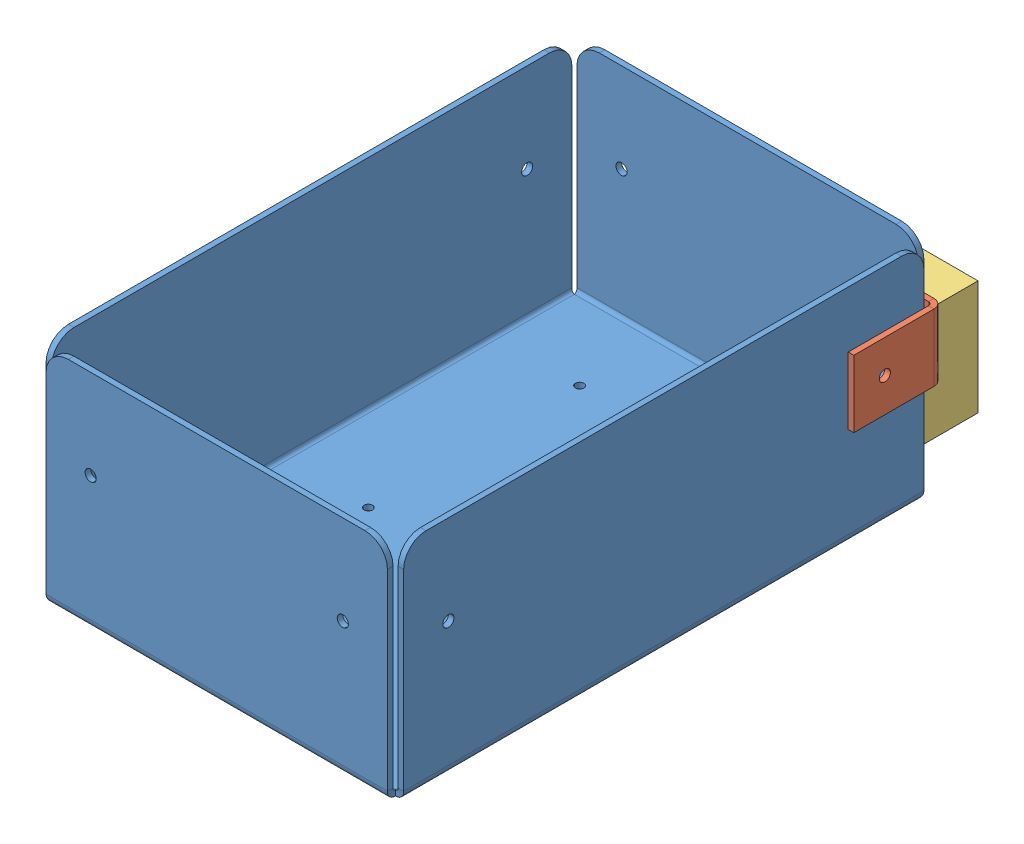
SolidWorks assembly Angle Placeholder, configuration Default. Lengths in mm.
Overall size (103.19 63.5 177.4).
3 component instances, 3 part files, 4 mates.
Components (placement in the parent):
- Main Box-1: Main Box [Default] at (15.8082 45.4395 190.7193) size (101.6 63.5 152.4)
- Angle-1: Angle [Default] at (93.5957 72.2938 38.3193) x (1 0 0) z (0 -1 0) size (25.4 25.4 19.05)
- Servo Mount-1: Servo Mount [Default] at (70.4703 78.4894 38.3193) x (1 0 0) z (0 1 0) size (35 25 32.5)
Mates (geometry in assembly coordinates):
- Coincident1: coincident anti-aligned: plane of Main Box-1 through (117.4082 45.4395 190.7193) normal (1 0 0); plane of Angle-1 through (117.4082 72.2938 38.3193) normal (-1 0 0)
- Coincident2: coincident anti-aligned: plane of Angle-1 through (93.5957 72.2938 38.3193) normal (0 0 1); plane of Main Box-1 through (15.8082 45.4395 38.3193) normal (0 0 -1)
- Distance2: distance = 9.525 mm: point of Main Box-1; line of Angle-1 through (118.9957 91.3438 39.3193) axis (0 0 1)
- Coincident5: coincident anti-aligned: plane of Main Box-1 through (15.8082 45.4395 38.3193) normal (0 0 -1); plane of Servo Mount-1 through (70.4703 78.4894 38.3193) normal (0 0 1)
